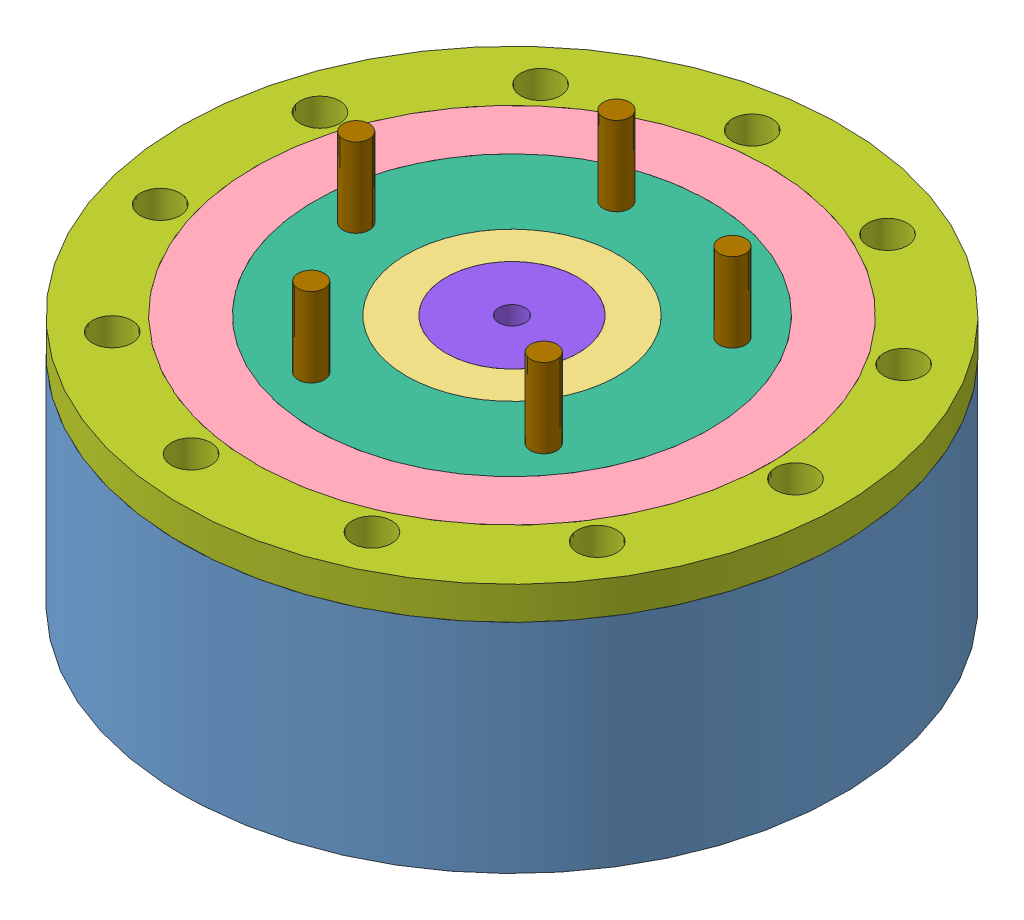
SolidWorks assembly Cycloidal Drive v1.1, configuration Default. Lengths in mm.
Overall size (106.79 50 108.65).
29 component instances, 10 part files, 74 mates.
Components (placement in the parent):
- Housing v1.2-2: Housing v1.2 [Default] at origin size (100 33 100)
- Cycloid v1.3-2: Cycloid v1.3 [Default] at (2.5 11 0) x (0.999377 0 0.035288) z (-0.035288 0 0.999377) size (83.12 7 86.15)
- Cycloid v1.3-3: Cycloid v1.3 [Default] at (-2.5 20 0) x (0.944602 0 -0.328218) z (0.328218 0 0.944602) size (83.12 7 86.15)
- 20x32x7-1: 20x32x7 [Default] at (-2.5 20 0) x (1 0 0) z (0 0 1) size (32 7 32)
- 20x32x7-2: 20x32x7 [Default] at (2.5 11 0) x (1 0 0) z (0 0 1) size (32 7 32)
- 20x32x7-3: 20x32x7 [Default] at (0 31 0) x (0.955673 0 0.294431) z (-0.294431 0 0.955673) size (32 7 32)
- 78x60x10-1: 78x60x10 [Default] x (0.999892 0 0.014665) z (-0.014665 0 0.999892) size (78 10 78)
- 78x60x10-2: 78x60x10 [Default] at (0 28 0) x (1 0 0) z (0 0 1) size (78 10 78)
- Dowel Pin-1: Dowel Pin [Default] at (17.8628 3 39.1142) size (6 30 6)
- Dowel Pin-2: Dowel Pin [Default] at (36.1739 3 23.2476) size (6 30 6)
- Dowel Pin-3: Dowel Pin [Default] at (-28.159 3 32.4972) size (6 30 6)
- Dowel Pin-4: Dowel Pin [Default] at (43 3 0) size (6 30 6)
- Dowel Pin-5: Dowel Pin [Default] at (-6.1195 3 42.5623) size (6 30 6)
- Dowel Pin-7: Dowel Pin [Default] at (17.8628 3 -39.1142) size (6 30 6)
- Dowel Pin-8: Dowel Pin [Default] at (-28.159 3 -32.4972) size (6 30 6)
- Dowel Pin-9: Dowel Pin [Default] at (-41.2582 3 12.1145) size (6 30 6)
- Dowel Pin-10: Dowel Pin [Default] at (-41.5434 3 -12.1428) x (1 0 -0.000071) z (0.000071 0 1) size (6 30 6)
- Dowel Pin-11: Dowel Pin [Default] at (-6.1028 3 -42.5932) size (6 30 6)
- Dowel Pin-12: Dowel Pin [Default] at (36.1739 3 -23.2476) size (6 30 6)
- TopCap-1: TopCap [Default] x (-0.999892 0 -0.014665) z (0 -1 0) size (60 60 10) (hidden)
- TopCap-2: TopCap [Default] at (0 28 0) x (-0.295036 0 -0.955486) z (0 -1 0) size (60 60 10)
- Top^Cycloidal Drive v1.1-1: Top^Cycloidal Drive v1.1 [Default] at (0 33 0) x (1 0 0) z (0 1 0) size (100 100 5) (virtual)
- Shaft-1: Shaft [Default] at origin size (36 38 36)
- Bolt-1: Bolt [Default] at (-7.7504 0 22.7141) x (-0.902128 0 0.431469) z (-0.431469 0 -0.902128) size (4 50 4)
- Bolt-2: Bolt [Default] at (-23.9974 0 -0.352) size (4 50 4)
- Bolt-3: Bolt [Default] at (-7.0809 0 -22.9317) x (0.60101 0 0.799241) z (-0.799241 0 0.60101) size (4 50 4)
- Bolt-4: Bolt [Default] at (19.6212 0 -13.8206) size (4 50 4)
- Bolt-5: Bolt [Default] at (19.2074 0 14.3901) x (0.25974 0 0.965678) z (-0.965678 0 0.25974) size (4 50 4)
- BottomCap^Cycloidal Drive v1.1-1: BottomCap^Cycloidal Drive v1.1 [Default] x (-0.999892 0 -0.014665) z (0 -1 0) size (60 60 10) (virtual)
Mates (geometry in assembly coordinates):
- Distance1: distance = 1 mm: plane of ? through (-16.4879 6 -39.0037) normal (0 -1 0); plane of ? through (0 5 0) normal (0 1 0)
- Concentric12: concentric: cylinder of ? through (0 5 0) axis (0 -1 0) radius 50; cylinder of ? through (0 -25 0) axis (0 1 0) radius 45.35
- Distance12: distance = 1 mm: plane of ? through (0 -1 0) normal (0 1 0); plane of ? through (0 0 0) normal (0 -1 0)
- Distance23: distance = 6 mm: plane of Cycloid v1.3-2 through (4.0174 11 -42.9732) normal (0 -1 0); plane of ? through (0 5 0) normal (0 1 0)
- Distance24: distance = 2 mm: plane of assembly; plane of assembly; plane of Cycloid v1.3-3 through (-16.6134 20 -40.6179) normal (0 -1 0); plane of Cycloid v1.3-2 through (4.0174 18 -42.9732) normal (0 1 0)
- Concentric13: concentric: circle of assembly; cylinder of assembly; circle of Cycloid v1.3-2; cylinder of 20x32x7-2 through (2.5 18 0) axis (0 -1 0) radius 16
- Distance25: distance = 0 mm: plane of assembly; plane of assembly; plane of 20x32x7-2 through (2.5 18 0) normal (0 1 0); plane of Cycloid v1.3-2 through (4.0174 18 -42.9732) normal (0 1 0)
- Concentric15: concentric: cylinder of assembly; cylinder of assembly; cylinder of Cycloid v1.3-3 through (-2.5 20 0) axis (0 1 0) radius 16; cylinder of 20x32x7-1 through (-2.5 27 0) axis (0 -1 0) radius 10
- Distance27: distance = 0 mm: plane of assembly; plane of assembly; plane of Cycloid v1.3-3 through (-16.6134 27 -40.6179) normal (0 1 0); plane of 20x32x7-1 through (-2.5 27 0) normal (0 1 0)
- Concentric16: concentric: cylinder of ? through (0 5 0) axis (0 -1 0) radius 50; cylinder of 20x32x7-3 through (0 38 0) axis (0 -1 0) radius 10
- Concentric17: concentric: cylinder of ? through (0 -1 0) axis (0 1 0) radius 39; cylinder of 78x60x10-1 through (0 10 0) axis (0 -1 0) radius 39
- Coincident9: coincident: plane of ? through (0 0 0) normal (0 -1 0); plane of 78x60x10-1 through (0 0 0) normal (0 -1 0)
- Concentric18: concentric: cylinder of assembly; cylinder of assembly; cylinder of 20x32x7-3 through (0 38 0) axis (0 -1 0) radius 16; cylinder of 78x60x10-2 through (0 38 0) axis (0 -1 0) radius 39
- Coincident10: coincident: plane of assembly; plane of assembly; plane of 20x32x7-3 through (0 38 0) normal (0 1 0); plane of 78x60x10-2 through (0 38 0) normal (0 1 0)
- Concentric19: concentric: cylinder of ? through (-28.159 49 32.4972) axis (0 -1 0) radius 3; cylinder of Dowel Pin-3 through (-28.159 33 32.4972) axis (0 -1 0) radius 3
- Concentric20: concentric: cylinder of ? through (-6.1195 49 42.5623) axis (0 -1 0) radius 3; cylinder of Dowel Pin-5 through (-6.1195 33 42.5623) axis (0 -1 0) radius 3
- Concentric21: concentric: cylinder of ? through (17.8628 49 39.1142) axis (0 -1 0) radius 3; cylinder of Dowel Pin-1 through (17.8628 33 39.1142) axis (0 -1 0) radius 3
- Concentric22: concentric: cylinder of ? through (36.1739 49 23.2476) axis (0 -1 0) radius 3; cylinder of Dowel Pin-2 through (36.1739 33 23.2476) axis (0 -1 0) radius 3
- Concentric23: concentric: cylinder of ? through (43 49 0) axis (0 -1 0) radius 3; cylinder of Dowel Pin-4 through (43 33 0) axis (0 -1 0) radius 3
- Concentric25: concentric: cylinder of ? through (-41.2582 49 12.1145) axis (0 -1 0) radius 3; cylinder of Dowel Pin-9 through (-41.2582 33 12.1145) axis (0 -1 0) radius 3
- Coincident11: coincident: circle of ?; cylinder of ? through (-41.2582 30 -12.1145) axis (0 -1 0) radius 3
- Concentric26: concentric: cylinder of ? through (-28.159 49 -32.4972) axis (0 -1 0) radius 3; cylinder of Dowel Pin-8 through (-28.159 33 -32.4972) axis (0 -1 0) radius 3
- Coincident12: coincident: circle of ?; cylinder of ? through (-6.1195 30 -42.5623) axis (0 -1 0) radius 3
- Concentric27: concentric: cylinder of ? through (17.8628 49 -39.1142) axis (0 -1 0) radius 3; cylinder of Dowel Pin-7 through (17.8628 33 -39.1142) axis (0 -1 0) radius 3
- Concentric28: concentric: circle of ?; circle of Dowel Pin-12
- Distance29: distance = 3 mm: plane of ? through (0 0 0) normal (0 -1 0); plane of Dowel Pin-12 through (36.1739 3 -23.2476) normal (0 -1 0)
- Distance30: distance = 3 mm: plane of ? through (0 0 0) normal (0 -1 0); plane of Dowel Pin-7 through (17.8628 3 -39.1142) normal (0 -1 0)
- Distance31: distance = 3 mm: plane of ? through (0 0 0) normal (0 -1 0); plane of Dowel Pin-11 through (-6.1028 3 -42.5932) normal (0 -1 0)
- Distance32: distance = 3 mm: plane of ? through (0 0 0) normal (0 -1 0); plane of Dowel Pin-8 through (-28.159 3 -32.4972) normal (0 -1 0)
- Distance33: distance = 3 mm: plane of ? through (0 0 0) normal (0 -1 0); plane of Dowel Pin-10 through (-41.5434 3 -12.1428) normal (0 -1 0)
- Distance34: distance = 3 mm: plane of ? through (0 0 0) normal (0 -1 0); plane of Dowel Pin-9 through (-41.2582 3 12.1145) normal (0 -1 0)
- Distance35: distance = 3 mm: plane of ? through (0 0 0) normal (0 -1 0); plane of Dowel Pin-3 through (-28.159 3 32.4972) normal (0 -1 0)
- Distance36: distance = 3 mm: plane of ? through (0 0 0) normal (0 -1 0); plane of Dowel Pin-5 through (-6.1195 3 42.5623) normal (0 -1 0)
- Distance37: distance = 3 mm: plane of ? through (0 0 0) normal (0 -1 0); plane of Dowel Pin-1 through (17.8628 3 39.1142) normal (0 -1 0)
- Distance38: distance = 3 mm: plane of ? through (0 0 0) normal (0 -1 0); plane of Dowel Pin-2 through (36.1739 3 23.2476) normal (0 -1 0)
- Distance39: distance = 3 mm: plane of ? through (0 0 0) normal (0 -1 0); plane of Dowel Pin-4 through (43 3 0) normal (0 -1 0)
- InPlace1: in place: plane of ? through (0 0 0) normal (0 -1 0); plane of ? through (0 0 0) normal (0 -1 0); moOrthogonalPlaneRef_w of ? through (0 0 0) normal (0 -1 0); plane of ? through (0 0 0) normal (0 0 -1); plane of ? through (0 0 0) normal (0 -1 0); plane of ? through (0 0 0) normal (-1 0 0); plane of 78x60x10-1 through (0 0 0) normal (0 -1 0); unknown of ?
- Coincident25: coincident: plane of assembly; plane of assembly; plane of 78x60x10-1; plane of TopCap-1
- Coincident26: coincident: unknown of 78x60x10-1; plane of ? through (0 0 0) normal (0.014665 0 -0.999892)
- Coincident27: coincident: unknown of 78x60x10-1; plane of ? through (0 0 0) normal (-0.999892 0 -0.014665)
- Concentric29: concentric: cylinder of assembly; cylinder of assembly; cylinder of 78x60x10-2 through (0 38 0) axis (0 -1 0) radius 30; cylinder of TopCap-2 through (0 38 0) axis (0 -1 0) radius 30
- Coincident25: coincident: plane of assembly; plane of assembly; plane of 78x60x10-2 through (0 38 0) normal (0 1 0); plane of TopCap-2 through (0 38 0) normal (0 1 0)
- Concentric30: concentric: cylinder of ? through (-23.9974 10 -0.352) axis (0 -1 0) radius 2; cylinder of TopCap-2 through (-23.9974 38 -0.352) axis (0 -1 0) radius 2
- Distance28: distance = 1 mm: plane of assembly; plane of assembly; plane of 78x60x10-2 through (0 28 0) normal (0 -1 0); plane of Cycloid v1.3-3 through (-16.6134 27 -40.6179) normal (0 1 0)
- InPlace3: in place: plane of ? through (0 0 0) normal (0 0 1); plane of ? through (0 0 0) normal (0 1 0); plane of ? through (0 0 0) normal (1 0 0); unknown of ?
- Coincident30: coincident: plane of assembly; plane of Shaft-1; plane of assembly
- Coincident31: coincident: plane of ? through (0 0 0) normal (0 1 0)
- Coincident32: coincident: plane of ? through (0 0 0) normal (1 0 0)
- Concentric34: concentric: cylinder of ? through (0 5 0) axis (0 -1 0) radius 50; cylinder of Top^Cycloidal Drive v1.1-1 through (0 38 0) axis (0 -1 0) radius 50
- Concentric35: concentric: circle of assembly; cylinder of assembly; circle of Dowel Pin-12; cylinder of Top^Cycloidal Drive v1.1-1 through (36.1739 38 -23.2476) axis (0 -1 0) radius 3
- Concentric38: concentric: cylinder of 20x32x7-1 through (-2.5 27 0) axis (0 -1 0) radius 10; cylinder of ? through (-2.5 28 0) axis (0 -1 0) radius 10
- Concentric39: concentric: cylinder of 20x32x7-2 through (2.5 18 0) axis (0 -1 0) radius 10; cylinder of ? through (2.5 19 0) axis (0 -1 0) radius 10
- Tangent1: tangent: cylinder of assembly; face of Cycloid v1.3-2; cylinder of Dowel Pin-10 through (-41.5434 33 -12.1428) axis (0 -1 0) radius 3
- Tangent2: tangent: cylinder of assembly; face of Cycloid v1.3-2; cylinder of Dowel Pin-8 through (-28.159 33 -32.4972) axis (0 -1 0) radius 3
- Tangent4: tangent: cylinder of assembly; face of Cycloid v1.3-3; cylinder of Dowel Pin-11 through (-6.1028 33 -42.5932) axis (0 -1 0) radius 3
- Tangent5: tangent: cylinder of assembly; face of Cycloid v1.3-3; cylinder of Dowel Pin-8 through (-28.159 33 -32.4972) axis (0 -1 0) radius 3
- Concentric40: concentric: cylinder of assembly; cylinder of assembly; cylinder of TopCap-2 through (19.2074 38 14.3901) axis (0 -1 0) radius 2; cylinder of Bolt-5 through (19.2074 50 14.3901) axis (0 -1 0) radius 2
- Coincident34: coincident: plane of ? through (0 0 0) normal (0 -1 0); plane of Bolt-5 through (19.2074 0 14.3901) normal (0 -1 0)
- Concentric41: concentric: cylinder of assembly; cylinder of assembly; cylinder of TopCap-2 through (-7.7504 38 22.7141) axis (0 -1 0) radius 2; cylinder of Bolt-1 through (-7.7504 50 22.7141) axis (0 -1 0) radius 2
- Coincident35: coincident: plane of assembly; plane of assembly; plane of Bolt-1 through (-7.7504 50 22.7141) normal (0 1 0); plane of Bolt-5 through (19.2074 50 14.3901) normal (0 1 0)
- Concentric42: concentric: cylinder of assembly; cylinder of assembly; cylinder of TopCap-2 through (-23.9974 38 -0.352) axis (0 -1 0) radius 2; cylinder of Bolt-2 through (-23.9974 50 -0.352) axis (0 -1 0) radius 2
- Coincident36: coincident: plane of assembly; plane of assembly; plane of Bolt-1 through (-7.7504 50 22.7141) normal (0 1 0); plane of Bolt-2 through (-23.9974 50 -0.352) normal (0 1 0)
- Concentric43: concentric: cylinder of assembly; cylinder of assembly; cylinder of TopCap-2 through (19.6212 38 -13.8206) axis (0 -1 0) radius 2; cylinder of Bolt-4 through (19.6212 50 -13.8206) axis (0 -1 0) radius 2
- Coincident37: coincident: plane of assembly; plane of assembly; plane of Bolt-2 through (-23.9974 0 -0.352) normal (0 -1 0); plane of Bolt-4 through (19.6212 0 -13.8206) normal (0 -1 0)
- Concentric44: concentric: cylinder of assembly; cylinder of assembly; cylinder of TopCap-2 through (-7.0809 38 -22.9317) axis (0 -1 0) radius 2; cylinder of Bolt-3 through (-7.0809 50 -22.9317) axis (0 -1 0) radius 2
- Coincident38: coincident: plane of assembly; plane of assembly; plane of Bolt-2 through (-23.9974 50 -0.352) normal (0 1 0); plane of Bolt-3 through (-7.0809 50 -22.9317) normal (0 1 0)
- Concentric48: concentric: cylinder of ? through (-0.9497 40 24.982) axis (0 -1 0) radius 2; cylinder of ? through (-0.9497 14 24.982) axis (0 -1 0) radius 4
- Coincident40: coincident: plane of ? through (-38.3954 11 -13.2878) normal (0 -1 0); plane of ? through (-0.9497 11 24.982) normal (0 -1 0)
- InPlace4: in place: plane of ? through (0 0 0) normal (0 -1 0); plane of ? through (0 0 0) normal (0 -1 0); plane of ? through (0 0 0) normal (0 -1 0); plane of ? through (0 0 0) normal (0 0 -1); plane of ? through (0 0 0) normal (0 -1 0); plane of ? through (0 0 0) normal (-1 0 0); plane of 78x60x10-1 through (0 0 0) normal (0 -1 0); unknown of ?
- Coincident41: coincident: plane of assembly; plane of assembly; plane of 78x60x10-1; plane of BottomCap^Cycloidal Drive v1.1-1
- Coincident42: coincident: unknown of 78x60x10-1; plane of ? through (0 0 0) normal (0.014665 0 -0.999892)
- Coincident43: coincident: unknown of 78x60x10-1; plane of ? through (0 0 0) normal (-0.999892 0 -0.014665)
- Coincident44: coincident: plane of ? through (0 33 0) normal (0 1 0); plane of Top^Cycloidal Drive v1.1-1 through (0 33 0) normal (0 -1 0)
- Concentric49: concentric: circle of ?; cylinder of ? through (0 -0.2675 0) axis (0 -1 0) radius 14.5
